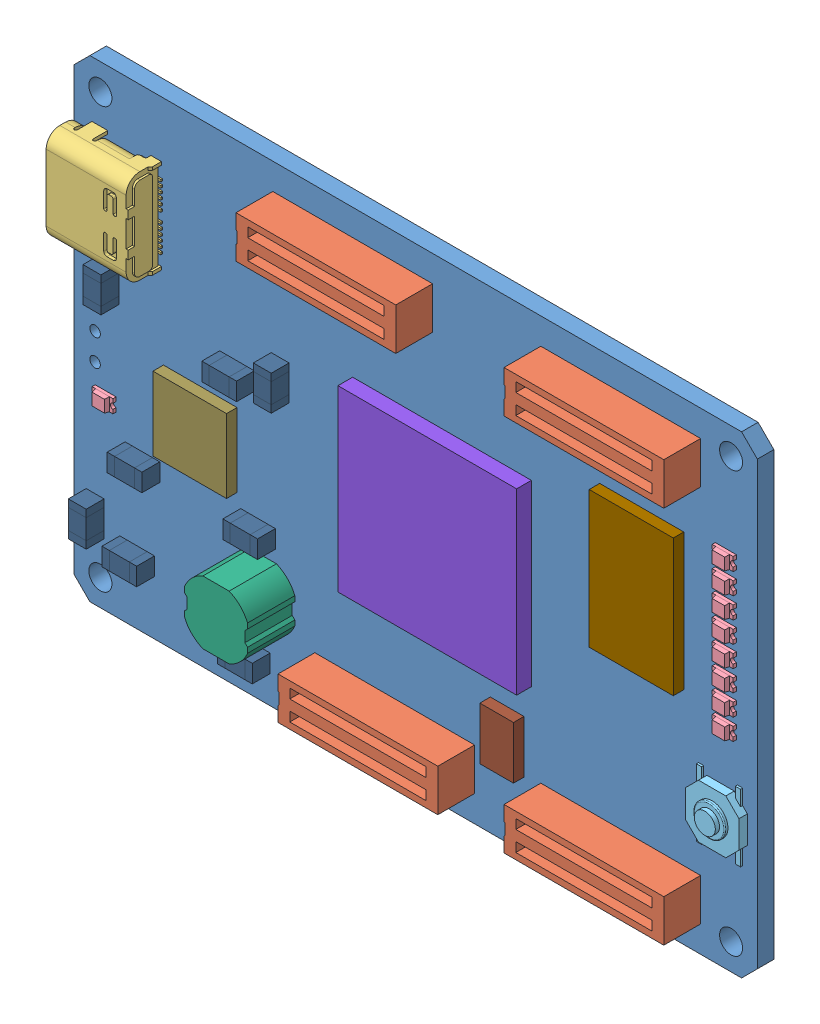
SolidWorks assembly Alchitry Au, configuration Default. Lengths in mm.
Overall size (65 45 8.47).
39 component instances, 13 part files, 0 mates.
Components (placement in the parent):
- Alchitry Au.iges-1: Alchitry Au.iges [Default] at origin size (65 45 8.47)
  - PCB v2.iges-1: PCB v2.iges [Default] at origin size (65 45 1.57)
  - Connector v1.iges-1: Connector v1.iges [Default] at (52 40.5 0) size (15.2 4 3.5)
  - Connector v1.iges-2: Connector v1.iges [Default] at (26.5 40.5 0) size (15.2 4 3.5)
  - Connector v1.iges-3: Connector v1.iges [Default] at (30.5 4.5 0) size (15.2 4 3.5)
  - Connector v1.iges-4: Connector v1.iges [Default] at (52 4.5 0) size (15.2 4 3.5)
  - USB Connector v1.iges-1: USB Connector v1.iges [Default] at (5.2 35.2 1.58) x (0 1 0) z (0 0 1) size (8.94 7.9 3.96)
  - LED 0805 v2.iges-1: LED 0805 v2.iges [Default] at (3 17.5 0) size (2 1.25 0.7)
  - LED 0805 v2.iges-2: LED 0805 v2.iges [Default] at (62 20 0) size (2 1.25 0.7)
  - LED 0805 v2.iges-3: LED 0805 v2.iges [Default] at (62 22 0) size (2 1.25 0.7)
  - LED 0805 v2.iges-4: LED 0805 v2.iges [Default] at (62 24 0) size (2 1.25 0.7)
  - LED 0805 v2.iges-5: LED 0805 v2.iges [Default] at (62 26 0) size (2 1.25 0.7)
  - LED 0805 v2.iges-6: LED 0805 v2.iges [Default] at (62 28 0) size (2 1.25 0.7)
  - LED 0805 v2.iges-7: LED 0805 v2.iges [Default] at (62 30 0) size (2 1.25 0.7)
  - LED 0805 v2.iges-8: LED 0805 v2.iges [Default] at (62 32 0) size (2 1.25 0.7)
  - LED 0805 v2.iges-9: LED 0805 v2.iges [Default] at (62 34 0) size (2 1.25 0.7)
  - Button v2.iges-1: Button v2.iges [Default] at (61.5 12.5 0) x (0 1 0) z (0 0 1) size (6.4 5.1 1.5)
  - Inductor 6mm v1.iges-1: Inductor 6mm v1.iges [Default] at (18 9 0) size (6 6 4.5)
  - Diode v1.iges-1: Diode v1.iges [Default] at (3.4 27.5 -1.57) x (0 -1 0) z (0 0 -1) size (5.4 2.7 2.4)
  - FPGA.iges-1: FPGA.iges [Default] at (55.712 -15.226 0) x (0 1 0) z (0 0 1) size (17 17 1.4)
  - DDR3.iges-1: DDR3.iges [Default] at (0.288 0.226 0) size (8 13 1)
  - 1206 Capacitor v1.iges-1: 1206 Capacitor v1.iges [Default] at (7.5 24.5 -3.27) x (0 -1 0) z (0 0 1) size (1.7 3.3 1.7)
  - 1206 Capacitor v1.iges-2: 1206 Capacitor v1.iges [Default] at (21.1 25.4 -3.27) size (1.7 3.3 1.7)
  - 1206 Capacitor v1.iges-3: 1206 Capacitor v1.iges [Default] at (22.5 20.3 -3.27) size (1.7 3.3 1.7)
  - 1206 Capacitor v1.iges-4: 1206 Capacitor v1.iges [Default] at (22.4 14.7 -3.27) size (1.7 3.3 1.7)
  - 1206 Capacitor v1.iges-5: 1206 Capacitor v1.iges [Default] at (25 14.7 -3.27) size (1.7 3.3 1.7)
  - 1206 Capacitor v1.iges-6: 1206 Capacitor v1.iges [Default] at (48.3 15.1 -3.27) size (1.7 3.3 1.7)
  - 1206 Capacitor v1.iges-7: 1206 Capacitor v1.iges [Default] at (38.6 32.6 -3.27) size (1.7 3.3 1.7)
  - 1206 Capacitor v1.iges-8: 1206 Capacitor v1.iges [Default] at (3.4 27.5 1.7) x (1 0 0) z (0 0 -1) size (1.7 3.3 1.7)
  - 1206 Capacitor v1.iges-9: 1206 Capacitor v1.iges [Default] at (15.5 26 1.7) x (0 1 0) z (0 0 -1) size (1.7 3.3 1.7)
  - 1206 Capacitor v1.iges-10: 1206 Capacitor v1.iges [Default] at (19.6 27.5 1.7) x (1 0 0) z (0 0 -1) size (1.7 3.3 1.7)
  - 1206 Capacitor v1.iges-11: 1206 Capacitor v1.iges [Default] at (17.5 14 1.7) x (0 1 0) z (0 0 -1) size (1.7 3.3 1.7)
  - 1206 Capacitor v1.iges-12: 1206 Capacitor v1.iges [Default] at (17 3.5 1.7) x (0 1 0) z (0 0 -1) size (1.7 3.3 1.7)
  - 1206 Capacitor v1.iges-13: 1206 Capacitor v1.iges [Default] at (6 6 1.7) x (0 1 0) z (0 0 -1) size (1.7 3.3 1.7)
  - 1206 Capacitor v1.iges-14: 1206 Capacitor v1.iges [Default] at (2 7.5 1.7) x (1 0 0) z (0 0 -1) size (1.7 3.3 1.7)
  - 1206 Capacitor v1.iges-15: 1206 Capacitor v1.iges [Default] at (6.5 14 1.7) x (0 1 0) z (0 0 -1) size (1.7 3.3 1.7)
  - Clock.iges-1: Clock.iges [Default] at (-0.4 20.7 1) x (1 0 0) z (0 0 -1) size (3.2 5 1)
  - Power IC.iges-1: Power IC.iges [Default] at (-2.5 39 1) x (1 0 0) z (0 0 -1) size (7 7 1)
  - FTDI.iges-1: FTDI.iges [Default] at (5.3279 43.045 -4.14) x (1 0 0) z (0 0 -1) size (9 9 1)
